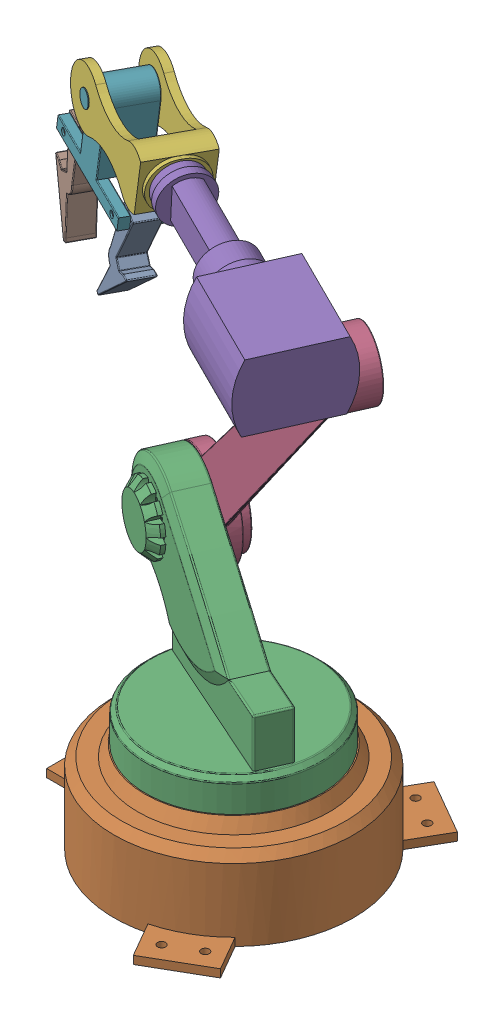
SolidWorks assembly Assembly_RoboticArm, configuration Default. Lengths in mm.
Overall size (552.27 765 389.18).
8 component instances, 7 part files, 14 mates.
Components (placement in the parent):
- Robotic_arm_gripper-1: Robotic_arm_gripper [Default] at (-57.5657 770.3397 223.0963) x (0.736917 -0.569994 0.363401) z (-0.544557 -0.819081 -0.180455) size (57.11 50 134.76)
- Robotic_arm_link01-1: Robotic_arm_link01 [Default] at (69.5858 168.9549 243.3848) size (344.57 145 377)
- Robotic_arm_link02-1: Robotic_arm_link02 [Default] at (69.5858 283.9549 243.3848) x (0.913411 0 0.407038) z (-0.407038 0 0.913411) size (310 220 220)
- Robotic_arm_link03-1: Robotic_arm_link03 [Default] at (-50.151 443.9549 168.1314) x (-0.614778 -0.739591 -0.273959) z (0.675551 -0.673057 0.301041) size (600 52 120)
- Robotic_arm_link04-1: Robotic_arm_link04 [Default] at (290.8701 852.8469 386.881) x (-0.407038 0 0.913411) z (-0.90928 0.095 -0.405197) size (121.7 130 291)
- Robotic_arm_link05-1: Robotic_arm_link05 [Default] at (20.7219 881.1293 269.2277) x (0.400513 -0.064912 -0.913989) z (0.90928 -0.095 0.405197) size (75 70 190.16)
- Robotic_arm_link06-1: Robotic_arm_link06 [Default] at (-94.185 812.1272 190.9526) x (-0.107267 -0.99395 0.023586) z (-0.400513 0.064912 0.913989) size (115 150 78)
- Robotic_arm_gripper-2: Robotic_arm_gripper [Default] at (-168.4468 780.3785 206.618) x (-0.907518 -0.165803 -0.385902) z (0.126492 -0.98402 0.125315) size (57.11 50 134.76)
Mates (geometry in assembly coordinates):
- Coincident1: coincident aligned: cylinder of Robotic_arm_link01-1 through (69.5858 313.9549 243.3848) axis (0 -1 0) radius 15; circle of Robotic_arm_link02-1
- Coincident2: coincident anti-aligned: plane of Robotic_arm_link01-1 through (69.5858 283.9549 243.3848) normal (0 1 0); plane of Robotic_arm_link02-1 through (69.5858 283.9549 243.3848) normal (0 -1 0)
- Concentric1: concentric aligned: cylinder of Robotic_arm_link02-1 through (-58.2918 443.9549 186.3996) axis (0.407038 0 -0.913411) radius 12.5; cylinder of Robotic_arm_link03-1 through (-58.2918 443.9549 186.3996) axis (0.407038 0 -0.913411) radius 15
- Coincident3: coincident anti-aligned: plane of Robotic_arm_link02-1 through (-13.6145 383.9549 184.4129) normal (0.407038 0 -0.913411); plane of Robotic_arm_link03-1 through (-50.151 443.9549 168.1314) normal (-0.407038 0 0.913411)
- Concentric2: concentric aligned: cylinder of Robotic_arm_link03-1 through (249.097 813.7505 323.3792) axis (0.407038 0 -0.913411) radius 15; cylinder of Robotic_arm_link04-1 through (249.097 813.7505 323.3792) axis (0.407038 0 -0.913411) radius 15
- Coincident4: coincident anti-aligned: plane of Robotic_arm_link03-1 through (-50.151 443.9549 168.1314) normal (-0.407038 0 0.913411); plane of Robotic_arm_link04-1 through (257.2378 813.7505 305.111) normal (0.407038 0 -0.913411)
- Concentric3: concentric aligned: cylinder of Robotic_arm_link04-1 through (36.2716 879.447 273.4259) axis (-0.90928 0.095 -0.405197) radius 15; cylinder of Robotic_arm_link05-1 through (44.4552 878.592 277.0727) axis (-0.90928 0.095 -0.405197) radius 15
- Coincident5: coincident anti-aligned: plane of Robotic_arm_link04-1 through (26.2696 880.492 268.9688) normal (-0.90928 0.095 -0.405197); plane of Robotic_arm_link05-1 through (25.2683 880.6543 271.2537) normal (0.90928 -0.095 0.405197)
- Coincident6: coincident anti-aligned: cylinder of Robotic_arm_link05-1 through (-81.5985 890.9941 179.9258) axis (-0.400513 0.064912 0.913989) radius 10; circle of Robotic_arm_link06-1
- Coincident7: coincident anti-aligned: plane of Robotic_arm_link05-1 through (19.088 884.9762 235.4154) normal (-0.400513 0.064912 0.913989); plane of Robotic_arm_link06-1 through (-85.6036 891.6432 189.0657) normal (0.400513 -0.064912 -0.913989)
- Coincident8: coincident anti-aligned: cylinder of Robotic_arm_gripper-1 through (-61.2167 802.7324 262.9601) axis (0.400513 -0.064912 -0.913989) radius 4; circle of Robotic_arm_link06-1
- Coincident9: coincident anti-aligned: plane of Robotic_arm_gripper-1 through (-60.9335 738.6371 223.872) normal (0.400513 -0.064912 -0.913989); plane of Robotic_arm_link06-1 through (-168.8494 804.6414 171.8953) normal (-0.400513 0.064912 0.913989)
- Concentric4: concentric aligned: cylinder of Robotic_arm_link06-1 through (-171.2166 813.4934 216.1817) axis (0.400513 -0.064912 -0.913989) radius 4; cylinder of Robotic_arm_gripper-2 through (-170.4156 813.3636 214.3537) axis (0.400513 -0.064912 -0.913989) radius 4
- Coincident10: coincident anti-aligned: plane of Robotic_arm_link06-1 through (-180.8648 806.5888 199.315) normal (0.400513 -0.064912 -0.913989); plane of Robotic_arm_gripper-2 through (-179.3506 750.5282 203.96) normal (-0.400513 0.064912 0.913989)
